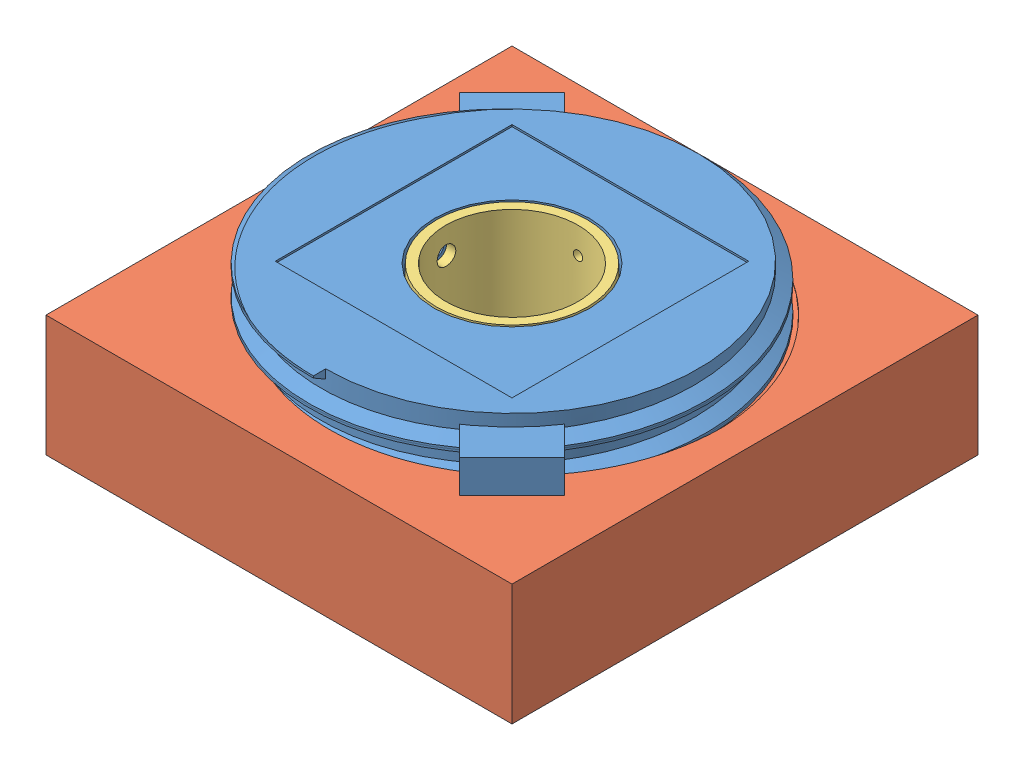
SolidWorks assembly ASIteration6, configuration Default. Lengths in mm.
Overall size (50 18.77 50).
3 component instances, 3 part files, 2 mates.
Components (placement in the parent):
- innerCircle-1: innerCircle [Default] at (0 2.7806 0) x (1 0 0.000011) z (-0.000011 0 1) size (44.82 17.61 43.01)
- Bottom-1: Bottom [Default] at (0 2.7806 0) x (0.000011 0 -1) z (0 1 0) size (50 50 14.08)
- innertubing-1: innertubing [Default] at (0 17.1931 0) x (1 0 0.000011) z (0 1 0) size (16.2 16.2 15.8)
Mates (geometry in assembly coordinates):
- Coincident2: coincident anti-aligned: line of innerCircle-1 through (16 0 18.7806) axis (0 0 -1); line of Bottom-1 through (10 0 0.7806) axis (0 0 1)
- Screw1: screw = 0.625 aligned: cylinder of innerCircle-1 through (0 18.7806 0) axis (0 -1 0) radius 20; cylinder of Bottom-1 through (0 13.7806 0) axis (0 -1 0) radius 20
